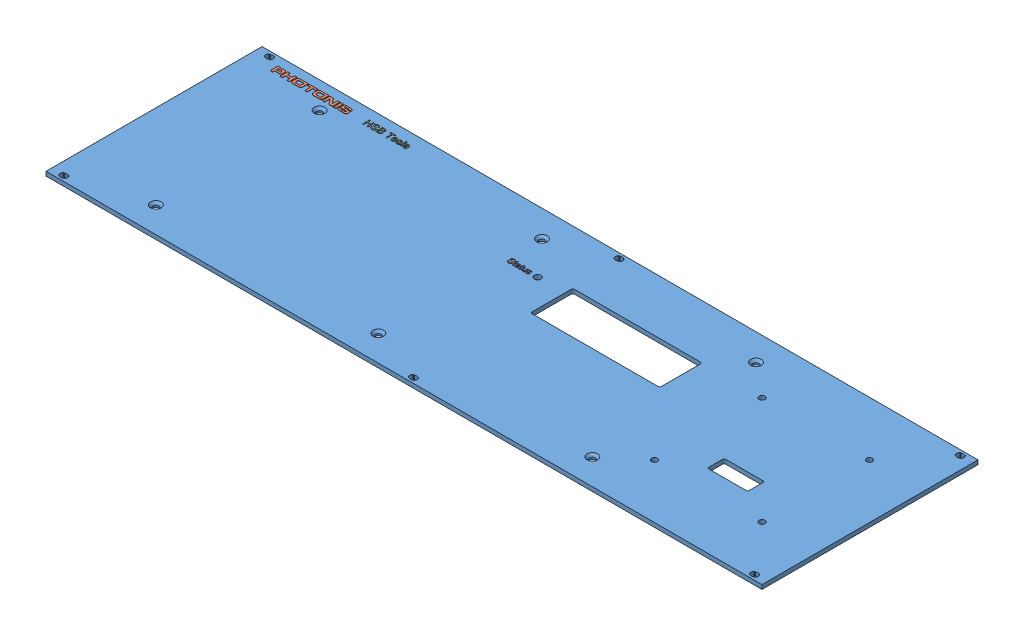
SolidWorks assembly MLA-0387-M12, configuration Default. Lengths in mm.
Overall size (426.52 2.65 128.7).
4 component instances, 4 part files, 9 mates.
Components (placement in the parent):
- MLA-0387-M1-1: MLA-0387-M1 [Default] at (-7.8975 -174.6729 597.0963) size (426.52 2.5 128.7)
- LOGO PHOTONIS-1: LOGO PHOTONIS [Default] at (9.7425 205.5771 259.7963) x (1 0 0) z (0 1 0) size (45.16 4.45 0.15)
- Tesla text-1: Tesla text [Default] at (64.2855 205.4271 259.8791) size (25.85 0.1 4.1)
- Status text-1: Status text [Default] at (178.1079 205.4271 288.0463) size (13.33 0.1 3.59)
Mates (geometry in assembly coordinates):
- Coincident1: coincident anti-aligned: plane of MLA-0387-M1-1 through (0.1829 205.4271 294.0204) normal (0 1 0); plane of LOGO PHOTONIS-1 through (13.9262 205.4271 256.4739) normal (0 -1 0)
- Distance1: distance = 15 mm aligned: plane of LOGO PHOTONIS-1 through (9.7425 205.4271 259.7963) normal (-1 0 0); plane of MLA-0387-M1-1 through (-5.2575 202.9271 334.0463) normal (-1 0 0)
- Distance2: distance = 10 mm anti-aligned: plane of LOGO PHOTONIS-1 through (11.1035 205.4271 259.7963) normal (0 0 1); plane of MLA-0387-M1-1 through (-5.2575 202.9271 249.7963) normal (0 0 -1)
- Coincident4: coincident anti-aligned: plane of MLA-0387-M1-1 through (0.1829 205.4271 294.0204) normal (0 1 0); plane of Tesla text-1 through (64.2855 205.4271 259.8791) normal (0 -1 0)
- Distance3: distance = 10 mm anti-aligned: plane of Tesla text-1 through (65.3066 205.5271 259.7963) normal (0 0 1); plane of MLA-0387-M1-1 through (-5.2575 202.9271 249.7963) normal (0 0 -1)
- Distance4: distance = 70 mm aligned: plane of Tesla text-1 through (64.7425 205.5271 259.7963) normal (-1 0 0); plane of MLA-0387-M1-1 through (-5.2575 202.9271 334.0463) normal (-1 0 0)
- Coincident7: coincident anti-aligned: plane of MLA-0387-M1-1 through (0.1829 205.4271 294.0204) normal (0 1 0); plane of Status text-1 through (178.7733 205.4271 287.7934) normal (0 -1 0)
- Distance5: distance = 38.25 mm anti-aligned: plane of Status text-1 through (189.1015 205.5271 288.0463) normal (0 0 1); plane of MLA-0387-M1-1 through (-5.2575 202.9271 249.7963) normal (0 0 -1)
- Distance6: distance = 187 mm: plane of Status text-1 through (181.7425 205.5271 287.3277) normal (-1 0 0); line of MLA-0387-M1-1 through (-5.2575 205.4271 378.4963) axis (0 0 -1)
